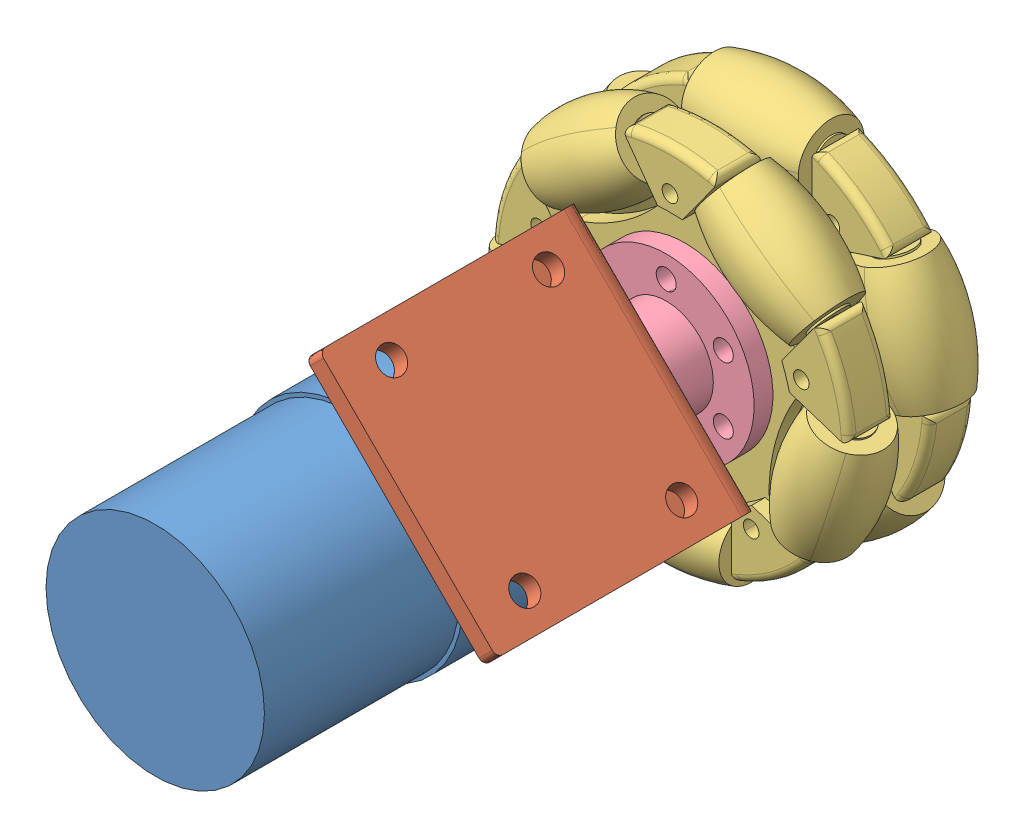
SolidWorks assembly 电机轮子组合体, configuration 默认. Lengths in mm.
Overall size (63.57 62.85 105.85).
5 component instances, 4 part files, 5 mates.
Components (placement in the parent):
- 直流减速电机-1: 直流减速电机 [默认] at (-52.9992 32.7906 -21.5) size (36 36 83)
- 电机支架-1: 电机支架 [默认] at (-80.2229 33.8513 -24.5) x (0.707107 0.707107 0) z (0.707107 -0.707107 0) size (41.5 42 40)
- 装配体2-1: 装配体2 [默认] at (-5.8497 18.178 -50.1348) size (63.57 62.85 36.45)
  - 60mm全向轮-1: 60mm全向轮 [默认] at (-33.7116 6.6664 -7.1915) size (63.57 62.85 28.43)
  - 全向轮联轴器-1: 全向轮联轴器 [默认] at (-47.1495 14.6126 7.2348) size (28 28 15)
Mates (geometry in assembly coordinates):
- 同心1: concentric aligned: cylinder of 直流减速电机-1 through (-52.9992 18.7906 -16.5) axis (0 0 -1) radius 1.5; cylinder of 电机支架-1 through (-52.9992 18.7906 -21.5) axis (0 0 -1) radius 1.6
- 同心2: concentric aligned: cylinder of 直流减速电机-1 through (-52.9992 46.7906 -16.5) axis (0 0 -1) radius 1.5; cylinder of 电机支架-1 through (-52.9992 46.7906 -21.5) axis (0 0 -1) radius 1.6
- 重合1: coincident anti-aligned: plane of 直流减速电机-1 through (-52.9992 32.7906 -21.5) normal (0 0 -1); plane of 电机支架-1 through (-51.9386 5.567 -21.5) normal (0 0 1)
- 同心3: concentric anti-aligned: cylinder of 直流减速电机-1 through (-52.9992 32.7906 -41.5) axis (0 0 1) radius 3; cylinder of 装配体2-1/全向轮联轴器-1 through (-52.9992 32.7906 -27.9) axis (0 0 -1) radius 3
- 距离3: distance = 16 mm anti-aligned: plane of 电机支架-1 through (-51.9386 5.567 -24.5) normal (0 0 -1); plane of 装配体2-1/60mm全向轮-1 through (-38.8548 13.3225 -40.5) normal (0 0 1)
